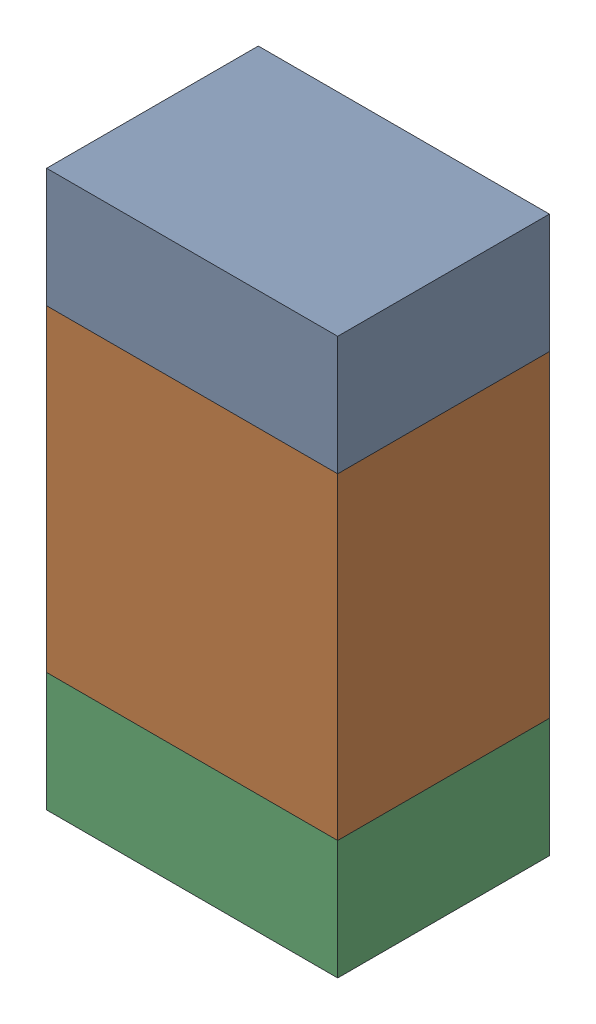
SolidWorks assembly R600_1PCB, configuration Default. Lengths in mm.
Overall size (0.55 1.05 0.4).
6 component instances, 2 part files, 0 mates.
Components (placement in the parent):
- 846483288-1: 846483288 [Default] at (105.7999 111.8124 -2.0638) size (0.55 0.22 0.4)
  - Extruded_12-1: Extruded_12 [Default] at origin size (0.55 0.22 0.4)
- 846483424-1: 846483424 [Default] at (105.7999 111.3999 -2.0638) size (0.55 0.6 0.4)
  - Extruded_13-1: Extruded_13 [Default] at origin size (0.55 0.6 0.4)
- 846483288-2: 846483288 [Default] at (105.7999 110.9874 -2.0638) size (0.55 0.22 0.4)
  - Extruded_12-1: Extruded_12 [Default] at origin size (0.55 0.22 0.4)
